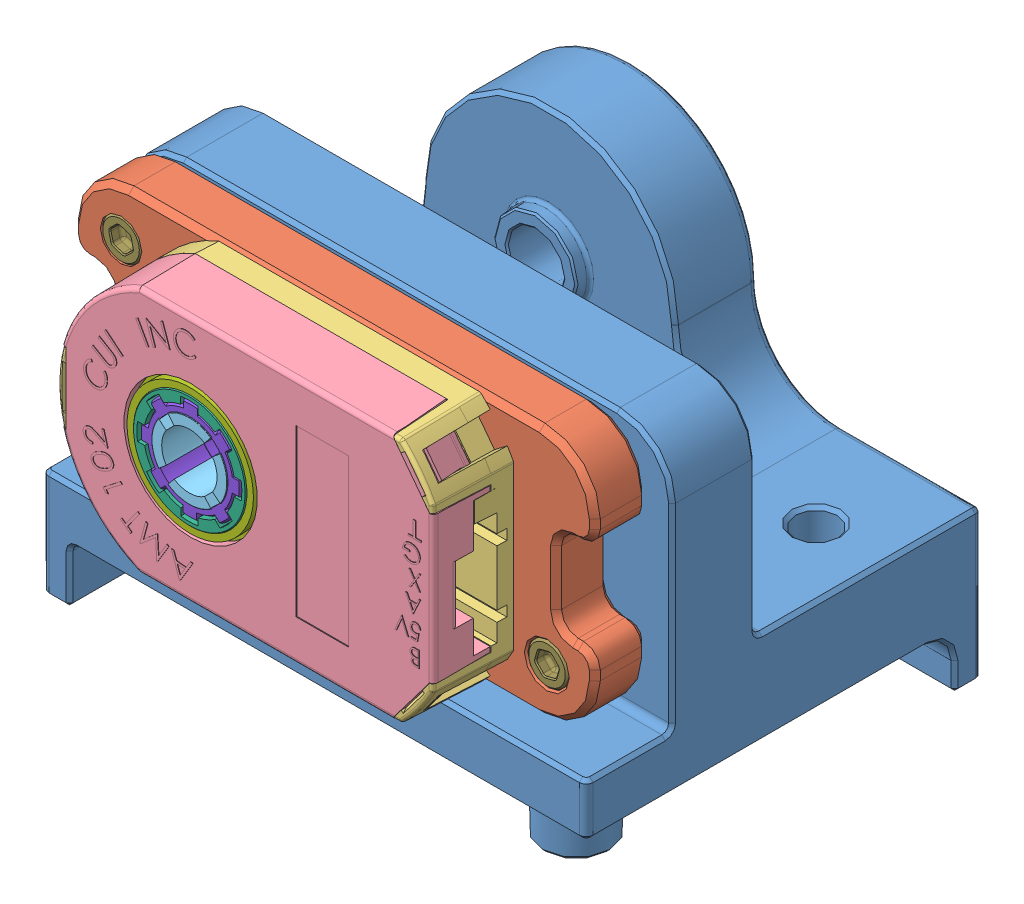
SolidWorks assembly 56+57+SlabAssembly, configuration Default. Lengths in mm.
Overall size (63.21 45.01 52.32).
17 component instances, 13 part files, 7 mates.
Components (placement in the parent):
- AARL_Puppy_18_01_01_056_R-1: AARL_Puppy_18_01_01_056_R [Default] at (-15.6391 107.954 87.1324) x (-1 0 0) z (0 0 -1)
- Slab_Assembly-1: Slab_Assembly [Default] at (56.243 111.4195 68.7964) size (59.83 36.33 21.74)
  - AARL_Puppy_18_01_01_055-1: AARL_Puppy_18_01_01_055 [Default] at (-49.6698 17.0323 53.8961) x (0 1 0) z (0 0 1) size (28.78 59.83 10.72)
  - CUI_DEVICES_cui_devices_amt102-0048-i6350-s-1: CUI_DEVICES_cui_devices_amt102-0048-i6350-s [Default] at (-49.6698 17.0323 63.6859) x (0 1 0) z (0 0 1) size (36.33 46.23 9.15)
    - CUI_DEVICES_amt-102-base-rev-k-1: CUI_DEVICES_amt-102-base-rev-k [Default] x (-1 0 0) z (0 0 -1) size (28.83 43.41 9.03)
    - CUI_DEVICES_amt-102-top-cover-rev-h-1: CUI_DEVICES_amt-102-top-cover-rev-h [Default] at (0 0 5.23) x (-1 0 0) z (0 0 -1) size (28.6 43.26 6.55)
    - CUI_DEVICES_amt-sleeve-rev-d(d)-1: CUI_DEVICES_amt-sleeve-rev-d(d) [Default] at (0 0 -2.42) x (0.999996 0.002864 0) z (0 0 1) size (10.79 10.79 7.8)
    - CUI_DEVICES_amt-hub-top-rev-d1-1: CUI_DEVICES_amt-hub-top-rev-d1 [Default] at (0 0 2.13) x (0.999996 0.002864 0) z (0 0 1) size (14 14 5.67)
    - CUI_DEVICES_amt-hub-bottom-rev-b-1: CUI_DEVICES_amt-hub-bottom-rev-b [Default] at (0 0 2.43) x (0.999998 -0.001942 0) z (0 0 1) size (17.3 17.3 3.2)
    - CUI_DEVICES_amt10x-shaft-adaptor-rev-e-1: CUI_DEVICES_amt10x-shaft-adaptor-rev-e [Default] at (0 0 0.03) x (0.999996 0.002864 0) z (0 0 1) size (11.8 11.8 7.8)
    - CUI_DEVICES_receiver-board-1: CUI_DEVICES_receiver-board [Default] at (72.2834 -20.351 3.03) x (-1 0 0) z (0 0 -1) size (26.5 26.62 0.41)
    - CUI_DEVICES_rotor-board-rev f-1: CUI_DEVICES_rotor-board-rev f [Default] at (0 0 2.13) x (0.807874 -0.589355 0) z (0 0 1) size (26 26 0.3)
    - CUI_DEVICES_transmitter-board amt10(amt-102)-1: CUI_DEVICES_transmitter-board amt10(amt-102) [Default] at (19.1596 -17.1102 1.22) x (-1 0 0) z (0 0 -1) size (26.63 38.43 4.41)
  - AARL_Puppy_18_04_01_017-2: AARL_Puppy_18_04_01_017 [Default] at (-66.6525 25.9223 59.9159) x (0.971112 0.238624 0) z (-0.238624 0.971112 0) size (4.65 12.57 4.65)
  - AARL_Puppy_18_04_01_017-3: AARL_Puppy_18_04_01_017 [Default] at (-17.8182 8.1423 59.8989) x (0.719542 0.694449 0) z (-0.694449 0.719542 0) size (4.65 12.57 4.65)
- 6377K310_ULTRA-LOW-FRICTION DRY-RUNNING SLEEVE BEARING-1: 6377K310_ULTRA-LOW-FRICTION DRY-RUNNING SLEEVE BEARING [6377K31] at (6.5859 128.4518 90.3074) x (0.990875 0.134785 0) z (0 0 1)
- 6377K310_ULTRA-LOW-FRICTION DRY-RUNNING SLEEVE BEARING-2: 6377K310_ULTRA-LOW-FRICTION DRY-RUNNING SLEEVE BEARING [6377K31] at (6.5859 128.4518 119.5174)
Mates (geometry in assembly coordinates):
- Concentric2: concentric aligned: cylinder of AARL_Puppy_18_01_01_056_R-1 through (18.5239 128.4518 119.3904) axis (0 0 1) radius 4.0323; cylinder of Slab_Assembly-1/AARL_Puppy_18_01_01_055-1 through (18.5239 128.4518 119.5174) axis (0 0 1) radius 3.9688
- Parallel1: parallel aligned: plane of AARL_Puppy_18_01_01_056_R-1 through (46.7814 142.9298 122.6924) normal (0 1 0); plane of Slab_Assembly-1/AARL_Puppy_18_01_01_055-1 through (43.9239 142.8409 128.7122) normal (0 1 0)
- Coincident2: coincident anti-aligned: plane of AARL_Puppy_18_01_01_056_R-1 through (46.7814 113.9738 122.6924) normal (0 0 1); plane of Slab_Assembly-1/AARL_Puppy_18_01_01_055-1 through (6.5732 128.4518 122.6924) normal (0 0 -1)
- Concentric3: concentric aligned: cylinder of AARL_Puppy_18_01_01_056_R-1 through (6.5859 128.4518 107.1324) axis (0 0 -1) radius 4.826; cylinder of 6377K310_ULTRA-LOW-FRICTION DRY-RUNNING SLEEVE BEARING-1 through (6.5859 128.4518 93.4824) axis (0 0 -1) radius 4.7752
- Coincident3: coincident anti-aligned: plane of AARL_Puppy_18_01_01_056_R-1 through (-15.6391 107.954 93.4824) normal (0 0 -1); plane of 6377K310_ULTRA-LOW-FRICTION DRY-RUNNING SLEEVE BEARING-1 through (6.5859 128.4518 93.4824) normal (0 0 1)
- Concentric4: concentric anti-aligned: cylinder of AARL_Puppy_18_01_01_056_R-1 through (6.5859 128.4518 102.6925) axis (0 0 1) radius 4.826; cylinder of 6377K310_ULTRA-LOW-FRICTION DRY-RUNNING SLEEVE BEARING-2 through (6.5859 128.4518 122.6924) axis (0 0 -1) radius 4.7752
- Coincident5: coincident anti-aligned: plane of AARL_Puppy_18_01_01_056_R-1 through (-15.6391 107.954 116.3424) normal (0 0 1); plane of 6377K310_ULTRA-LOW-FRICTION DRY-RUNNING SLEEVE BEARING-2 through (6.5859 128.4518 116.3424) normal (0 0 -1)
